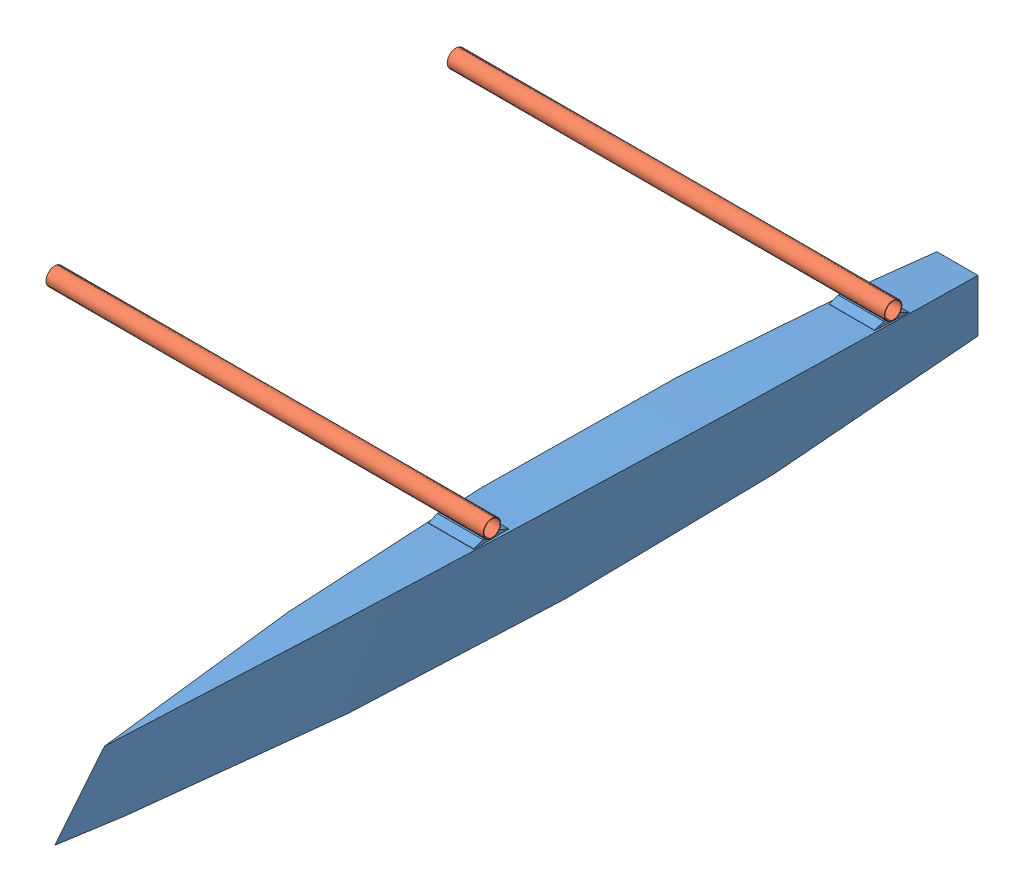
SolidWorks assembly кат, configuration Default. Lengths in mm.
Overall size (2537.7 589.09 5161.22).
2 component instances, 2 part files, 2 mates.
Components (placement in the parent):
- поплавок-1: поплавок [Default] at (-47.3954 -135.2834 2594.5622) size (337.08 505.15 5161.22)
- балкиКат-1: балкиКат [Default] at (84.9135 248.8518 -2066.6541) x (0 -0.029571 -0.999563) z (-1 0 0) size (2395 100 2500)
Mates (geometry in assembly coordinates):
- Concentric7: concentric anti-aligned: cylinder of поплавок-1 through (82.6046 316.7166 227.3422) axis (-1 0 0) radius 51; cylinder of балкиКат-1 through (-2415.0865 316.7166 227.3422) axis (1 0 0) radius 50
- Concentric8: concentric anti-aligned: cylinder of поплавок-1 through (82.6046 248.8518 -2066.6541) axis (-1 0 0) radius 51; cylinder of балкиКат-1 through (-2415.0865 248.8518 -2066.6541) axis (1 0 0) radius 50
